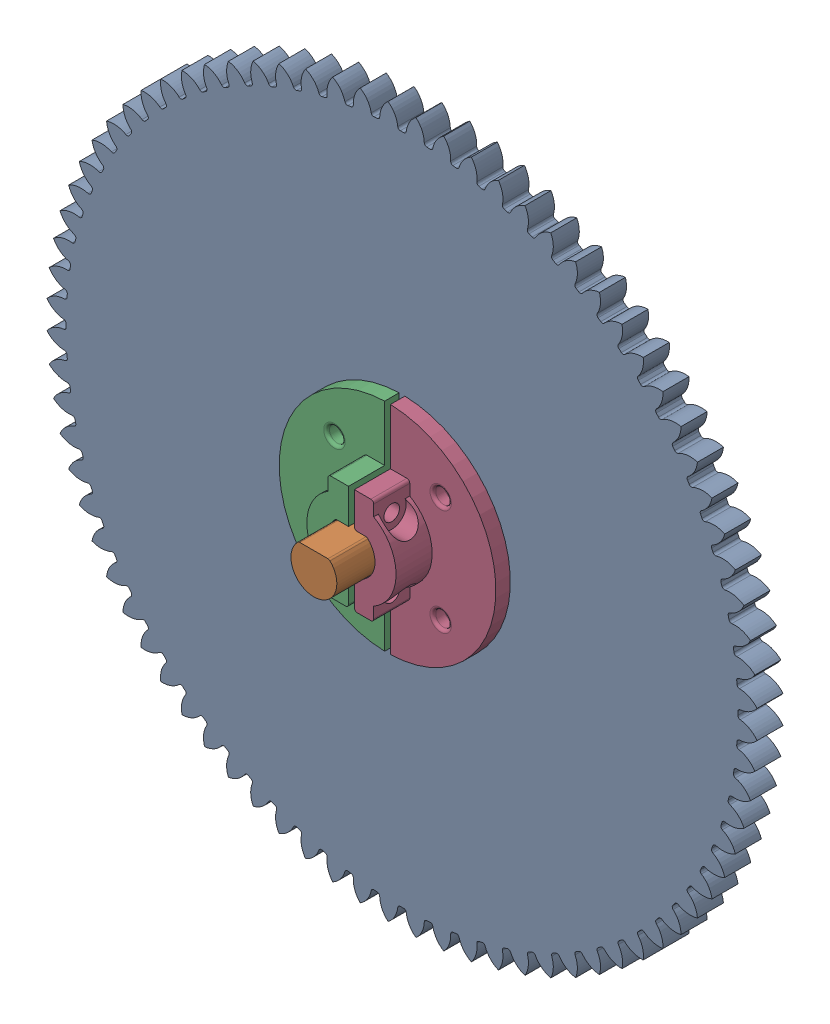
SolidWorks assembly Output Shaft, configuration Default. Lengths in mm.
Overall size (245.77 245.77 100).
4 component instances, 3 part files, 7 mates.
Components (placement in the parent):
- Driven15_88mm-1: Driven15_88mm [Default] at (-27.891 -3.1331 4.2868) size (245.77 245.77 9)
- 15.88mm shaft-1: 15.88mm shaft [Default] at (-27.891 -3.1331 -56.2132) x (0 0 1) z (-1 0 0) size (100 13.88 15.88)
- SplitCollar15_88mmBore-1: SplitCollar15_88mmBore [Default] at (-27.891 -3.1331 13.2868) size (75 74.97 17.5)
- SplitCollar15_88mmBore-2: SplitCollar15_88mmBore [Default] at (-27.891 -3.1331 4.2868) x (-1 0 0) z (0 0 -1) size (75 74.97 17.5)
Mates (geometry in assembly coordinates):
- Concentric1: concentric anti-aligned: cylinder of Driven15_88mm-1 through (-27.891 -3.1331 4.2868) axis (0 0 1) radius 7.915; cylinder of 15.88mm shaft-1 through (-27.891 -3.1331 42.7868) axis (0 0 -1) radius 7.94
- Parallel1: parallel anti-aligned: plane of Driven15_88mm-1 through (-32.5272 3.2819 4.2868) normal (0 -1 0); plane of 15.88mm shaft-1 through (-27.891 2.8069 -57.2132) normal (0 1 0)
- Concentric2: concentric aligned: cylinder of 15.88mm shaft-1 through (-27.891 -3.1331 42.7868) axis (0 0 -1) radius 7.94; cylinder of SplitCollar15_88mmBore-1 through (-27.891 -3.1331 30.7868) axis (0 0 -1) radius 8.15
- Coincident2: coincident anti-aligned: plane of Driven15_88mm-1 through (-27.891 -3.1331 13.2868) normal (0 0 1); plane of SplitCollar15_88mmBore-1 through (-27.891 -3.1331 13.2868) normal (0 0 -1)
- Coincident3: coincident anti-aligned: plane of Driven15_88mm-1 through (-27.891 -3.1331 4.2868) normal (0 0 -1); plane of SplitCollar15_88mmBore-2 through (-27.891 -3.1331 4.2868) normal (0 0 1)
- Concentric3: concentric anti-aligned: cylinder of 15.88mm shaft-1 through (-27.891 -3.1331 42.7868) axis (0 0 -1) radius 7.94; cylinder of SplitCollar15_88mmBore-2 through (-27.891 -3.1331 -13.2132) axis (0 0 1) radius 8.15
- Distance1: distance = 13 mm aligned: plane of SplitCollar15_88mmBore-1 through (-27.891 -3.1331 30.7868) normal (0 0 1); plane of 15.88mm shaft-1 through (-27.891 -3.1331 43.7868) normal (0 0 1)
